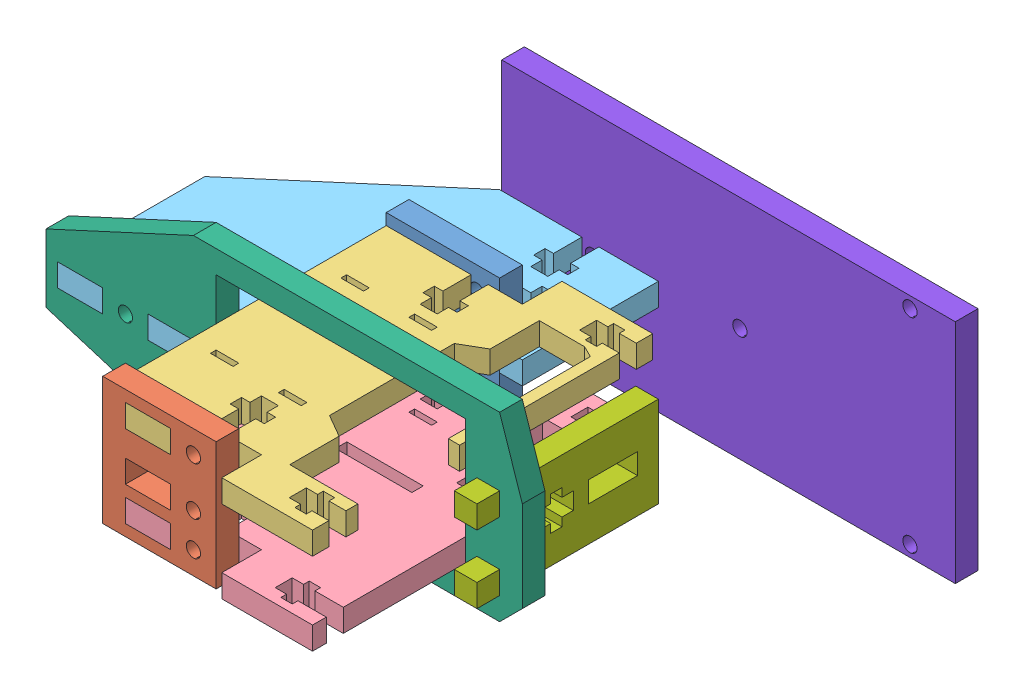
SolidWorks assembly Camera, configuration Default. Lengths in mm.
Overall size (175.21 63.5 128.59).
8 component instances, 8 part files, 21 mates.
Components (placement in the parent):
- MirrorCameraSide-3: MirrorCameraSide [Default] at (-10.4832 -121.8345 58.7991) x (1 0 0) z (0 0 -1) size (31.75 35.72 6.35)
- CameraSide-3: CameraSide [Default] at (-10.4832 -121.8345 144.5241) x (1 0 0) z (0 0 -1) size (31.75 35.72 6.35)
- CameraBottom-2: CameraBottom [Default] at (-10.4832 -131.3595 119.1241) size (63.5 6.35 95.25)
- CameraTopHack-3: CameraTopHack [Default] at (-10.4832 -148.0283 84.1991) x (1 0 0) z (0 0 -1) size (63.5 6.35 95.25)
- CameraHang-1: CameraHang [Default] at (27.6168 -138.5033 65.1491) x (0 -1 0) z (1 0 0) size (6.35 85.72 88.9)
- FrontIRHack-2: FrontIRHack [Default] at (53.0168 -119.4533 106.4241) x (0 -1 0) z (1 0 0) size (50.8 6.35 133.35)
- FrontIR-1: FrontIR [Default] at (62.5418 -144.8533 87.3741) x (0 1 0) z (-1 0 0) size (25.4 50.8 6.35)
- CameraTopTop-2: CameraTopTop [Default] at (110.7468 -106.7533 27.0491) x (0 -1 0) z (1 0 0) size (63.5 6.35 127)
Mates (geometry in assembly coordinates):
- Coincident21: coincident anti-aligned: plane of CameraSide-3 through (-4.1332 -125.0095 138.1741) normal (0 -1 0); plane of CameraBottom-2 through (-10.4832 -125.0095 119.1241) normal (0 1 0)
- Coincident22: coincident anti-aligned: plane of CameraSide-3 through (8.5668 -131.3595 138.1741) normal (-1 0 0); plane of CameraBottom-2 through (8.5668 -125.0095 119.1241) normal (1 0 0)
- Coincident23: coincident anti-aligned: plane of CameraSide-3 through (-10.4832 -121.8345 138.1741) normal (0 0 -1); plane of CameraBottom-2 through (-10.4832 -125.0095 138.1741) normal (0 0 1)
- Coincident24: coincident anti-aligned: plane of MirrorCameraSide-3 through (-4.1332 -125.0095 65.1491) normal (0 -1 0); plane of CameraBottom-2 through (-10.4832 -125.0095 119.1241) normal (0 1 0)
- Coincident25: coincident anti-aligned: plane of MirrorCameraSide-3 through (8.5668 -131.3595 65.1491) normal (-1 0 0); plane of CameraBottom-2 through (8.5668 -125.0095 119.1241) normal (1 0 0)
- Coincident26: coincident anti-aligned: plane of MirrorCameraSide-3 through (-10.4832 -121.8345 65.1491) normal (0 0 1); plane of CameraBottom-2 through (-10.4832 -125.0095 65.1491) normal (0 0 -1)
- Coincident27: coincident anti-aligned: plane of MirrorCameraSide-3 through (8.5668 -148.0283 65.1491) normal (0 -1 0); plane of CameraTopHack-3 through (-10.4832 -148.0283 84.1991) normal (0 1 0)
- Coincident28: coincident anti-aligned: plane of CameraSide-3 through (-10.4832 -121.8345 138.1741) normal (0 0 -1); plane of CameraTopHack-3 through (-10.4832 -154.3783 138.1741) normal (0 0 1)
- Coincident29: coincident anti-aligned: plane of CameraSide-3 through (-4.1332 -148.0283 138.1741) normal (1 0 0); plane of CameraTopHack-3 through (-4.1332 -154.3783 84.1991) normal (-1 0 0)
- Coincident30: coincident anti-aligned: plane of MirrorCameraSide-3 through (-10.4832 -121.8345 58.7991) normal (0 0 -1); plane of CameraHang-1 through (27.6168 -144.8533 58.7991) normal (0 0 1)
- Coincident31: coincident anti-aligned: plane of MirrorCameraSide-3 through (-4.1332 -144.8533 65.1491) normal (0 1 0); plane of CameraHang-1 through (27.6168 -144.8533 65.1491) normal (0 -1 0)
- Coincident32: coincident anti-aligned: plane of MirrorCameraSide-3 through (8.5668 -144.8533 65.1491) normal (-1 0 0); plane of CameraHang-1 through (8.5668 -144.8533 65.1491) normal (1 0 0)
- Coincident37: coincident: plane of CameraHang-1 through (27.6168 -144.8533 65.1491) normal (0 -1 0); plane of FrontIRHack-2 through (53.0168 -144.8533 100.0741) normal (0 1 0)
- Coincident38: coincident: plane of CameraHang-1 through (27.6168 -144.8533 100.0741) normal (0 0 1); plane of FrontIRHack-2 through (53.0168 -119.4533 100.0741) normal (0 0 -1)
- Coincident39: coincident anti-aligned: plane of CameraHang-1 through (-61.2832 -144.8533 65.1491) normal (-1 0 0); plane of FrontIRHack-2 through (-61.2832 -119.4533 100.0741) normal (1 0 0)
- Coincident40: coincident: plane of FrontIRHack-2 through (62.5418 -119.4533 100.0741) normal (-1 0 0); plane of FrontIR-1 through (62.5418 -144.8533 87.3741) normal (1 0 0)
- Coincident41: coincident: plane of FrontIRHack-2 through (53.0168 -151.2033 100.0741) normal (0 -1 0); plane of FrontIR-1 through (56.1918 -151.2033 100.0741) normal (0 1 0)
- Coincident42: coincident anti-aligned: plane of FrontIRHack-2 through (53.0168 -119.4533 100.0741) normal (0 0 -1); plane of FrontIR-1 through (56.1918 -151.2033 100.0741) normal (0 0 1)
- Coincident43: coincident: plane of CameraHang-1 through (27.6168 -144.8533 27.0491) normal (0 0 -1); plane of CameraTopTop-2 through (110.7468 -106.7533 27.0491) normal (0 0 1)
- Coincident44: coincident: plane of CameraHang-1 through (27.6168 -144.8533 65.1491) normal (0 -1 0); plane of CameraTopTop-2 through (2.2168 -144.8533 27.0491) normal (0 1 0)
- Coincident45: coincident anti-aligned: plane of CameraHang-1 through (2.2168 -144.8533 65.1491) normal (1 0 0); plane of CameraTopTop-2 through (2.2168 -138.5033 27.0491) normal (-1 0 0)
